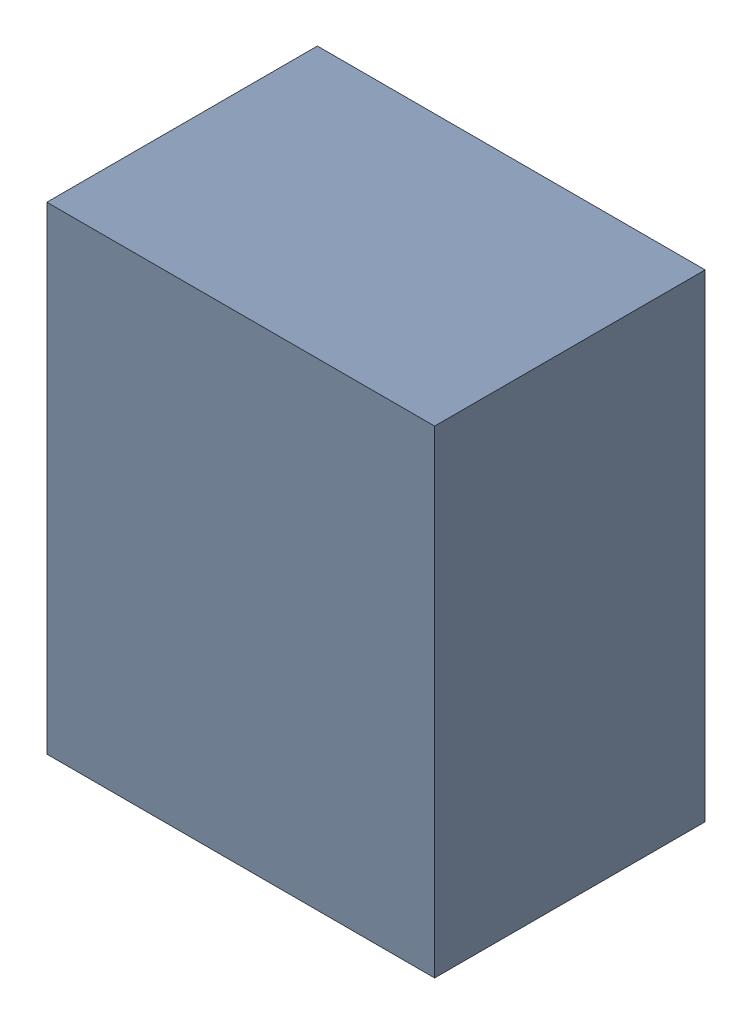
SolidWorks assembly LD1, configuration Default. Lengths in mm.
Overall size (3.01 3.71 2.1).
2 component instances, 1 part files, 0 mates.
Components (placement in the parent):
- 1088889872-1: 1088889872 [Default] at (1.905 46.863 0) size (3.01 3.71 2.1)
  - Extruded-34-1: Extruded-34 [Default] at origin size (3.01 3.71 2.1)
